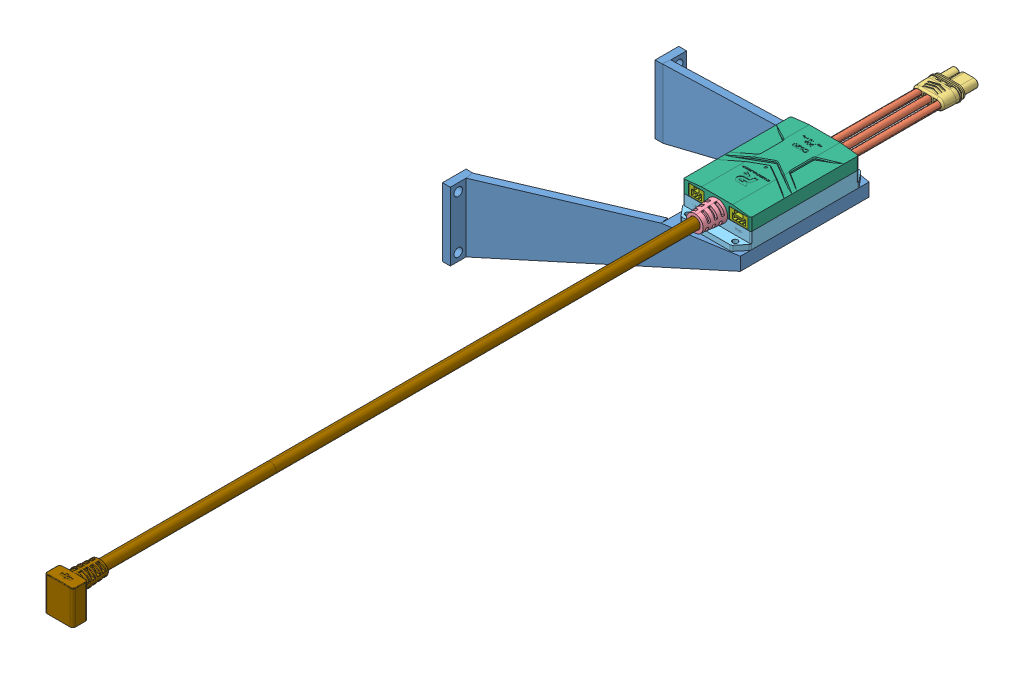
SolidWorks assembly 3508Protect, configuration 默认. Lengths in mm.
Overall size (93 50.48 345.36).
17 component instances, 9 part files, 3 mates.
Components (placement in the parent):
- 3508Protect-1: 3508Protect [默认] at (-47.7469 -0.7317 48.1829) size (93 38 90)
- C620无刷电机调速器-1: C620无刷电机调速器 [默认] at (32.3531 23.5845 91.3) x (0 0 -1) z (-1 0 0) size (345.36 15.69 26.13)
  - C620无刷电机调速器.STEP-1: C620无刷电机调速器.STEP [Default] at origin size (345.36 15.69 26.13)
    - 9.STEP-1: 9.STEP [Default] at (63.0501 2 0) x (0 0 1) z (1 0 0) size (12.31 5.31 60.01)
      - 14.STEP-1: 14.STEP [默认] at (4 0 -0.7) size (2.5 2.5 50)
      - 14.STEP-2: 14.STEP [默认] at (0 0 -0.7) x (0.422263 0.906473 0) z (0 0 1) size (2.5 2.5 50)
      - 14.STEP-3: 14.STEP [默认] at (-4 0 -0.7) size (2.5 2.5 50)
      - 1.STEP-1: 1.STEP [默认] at (-18.7519 0 2.7064) x (-1 0 0) z (0 0 1) size (12.31 5.31 14.5)
    - 6.STEP-1: 6.STEP [默认] at (-2.2 39.826 -7.4409) x (0 -0.431667 0.902033) z (-1 0 0) size (8.67 8.67 10.5)
    - 7.STEP-1: 7.STEP [默认] at (-1.7 0.6 0) size (49.4 6 25.8)
    - 8.STEP-1: 8.STEP [默认] at (-1.7 -0.6 0) x (0 -1 0) z (0 0 1) size (6.5 41 25.8)
    - 2.STEP-1: 2.STEP [默认] at (15.6004 -0.6014 9.8) x (0 0 -1) z (0 1 0) size (24.83 40.8 4.35)
    - 5.STEP-1: 5.STEP [默认] at (16.6 -3.6 -10.7) x (-0.36263 0 0.931933) z (-0.931933 0 -0.36263) size (3 9 3)
    - 5.STEP-2: 5.STEP [默认] at (16.6 -3.6 10.7) size (3 9 3)
    - 5.STEP-3: 5.STEP [默认] at (-14.3 -3.6 10.7) size (3 9 3)
    - 5.STEP-4: 5.STEP [默认] at (-14.3 -3.6 -10.7) size (3 9 3)
    - 10.STEP-1: 10.STEP [默认] at (-177.4931 0.4104 -3.9137) x (1 0 0) z (0 -1 0) size (250.81 10.82 13.76)
Mates (geometry in assembly coordinates):
- 重合1: coincident: plane of assembly; plane of assembly; plane of 3508Protect-1 through (45.2531 18.1845 118.0001) normal (0 1 0); plane of C620无刷电机调速器-1/C620无刷电机调速器.STEP-1/7.STEP-1 through (32.3531 18.1845 93.0001) normal (0 -1 0)
- 重合2: coincident: plane of assembly; plane of assembly; plane of 3508Protect-1 through (45.2531 -0.7317 48.1829) normal (1 0 0); plane of C620无刷电机调速器-1/C620无刷电机调速器.STEP-1/7.STEP-1 through (45.2531 19.1845 113.5001) normal (1 0 0)
- 宽度1: width: plane of assembly; plane of assembly; plane of assembly; plane of assembly; plane of 3508Protect-1 through (-44.7469 -0.7317 138.0001) normal (0 0 1); plane of 3508Protect-1 through (-44.7469 -0.7317 48.0001) normal (0 0 -1); plane of C620无刷电机调速器-1/C620无刷电机调速器.STEP-1/7.STEP-1 through (32.3531 20.1845 68.3) normal (0 0 -1); plane of C620无刷电机调速器-1/C620无刷电机调速器.STEP-1/7.STEP-1 through (45.2531 20.1845 117.7001) normal (0 0 1)
